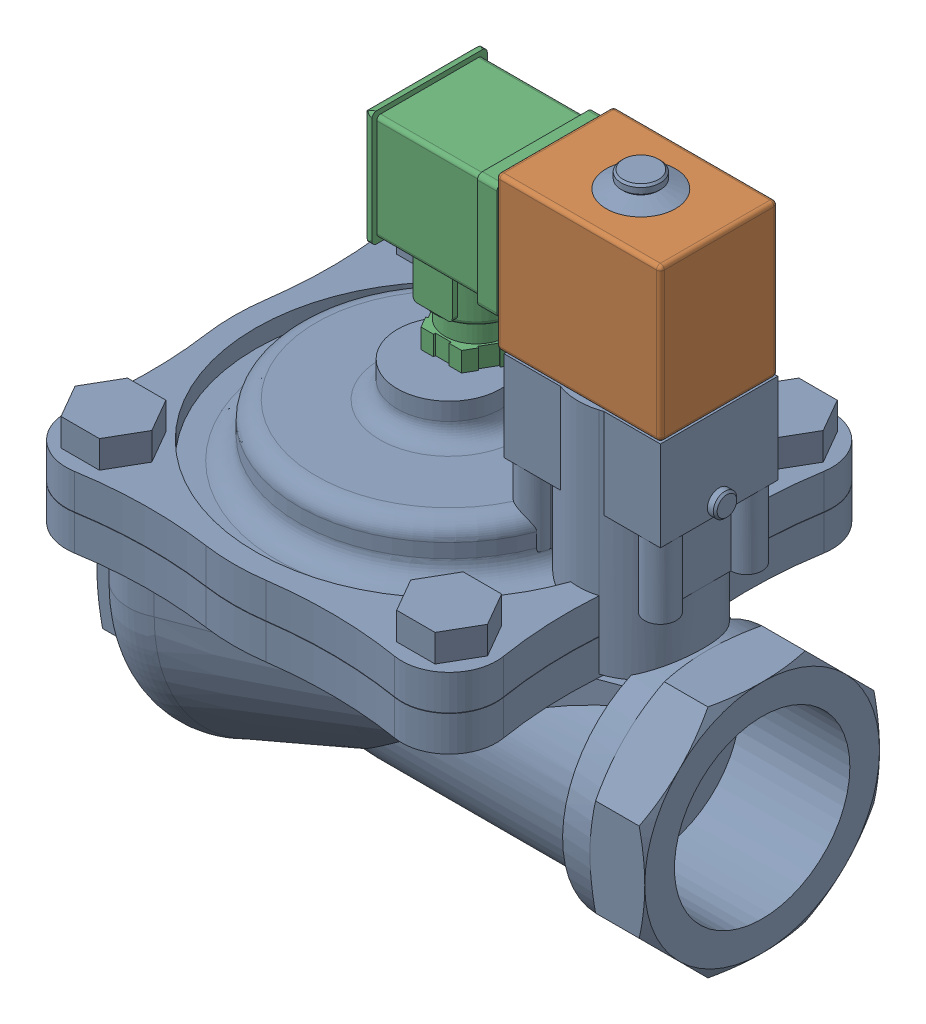
SolidWorks assembly solenoid_valve_sc_g238c020_3b_oh, configuration Default. Lengths in mm.
Overall size (140 159.5 110).
3 component instances, 3 part files, 3 mates.
Components (placement in the parent):
- solenoid_valve_1b_3b_oh-1: solenoid_valve_1b_3b_oh [Default] at origin size (140 159.5 110)
- solenoid_valve_2b_3b_3b_oh-1: solenoid_valve_2b_3b_3b_oh [Default] at origin size (54 39 30)
- solenoid_valve_3b_3b_3b_oh-1: solenoid_valve_3b_3b_3b_oh [Default] at (0 212 0) x (1 0 0) z (0 0 -1) size (37.4 51.76 29.51)
Mates (geometry in assembly coordinates):
- Concentric4: concentric: cylinder of solenoid_valve_2b_3b_3b-1 through (87 106 0) axis (-1 0 0) radius 1.2294; cylinder of solenoid_valve_3b_3b_3b-1 through (89.4 106 0) axis (-1 0 0) radius 1.5
- Coincident5: coincident anti-aligned: plane of solenoid_valve_2b_3b_3b-1 through (87 0 0) normal (-1 0 0); plane of solenoid_valve_3b_3b_3b-1 through (87 212 0) normal (1 0 0)
- Parallel1: parallel aligned: plane of solenoid_valve_2b_3b_3b-1 through (0 123.7 0) normal (0 1 0); plane of solenoid_valve_3b_3b_3b-1 through (0 119.5 0) normal (0 1 0)
